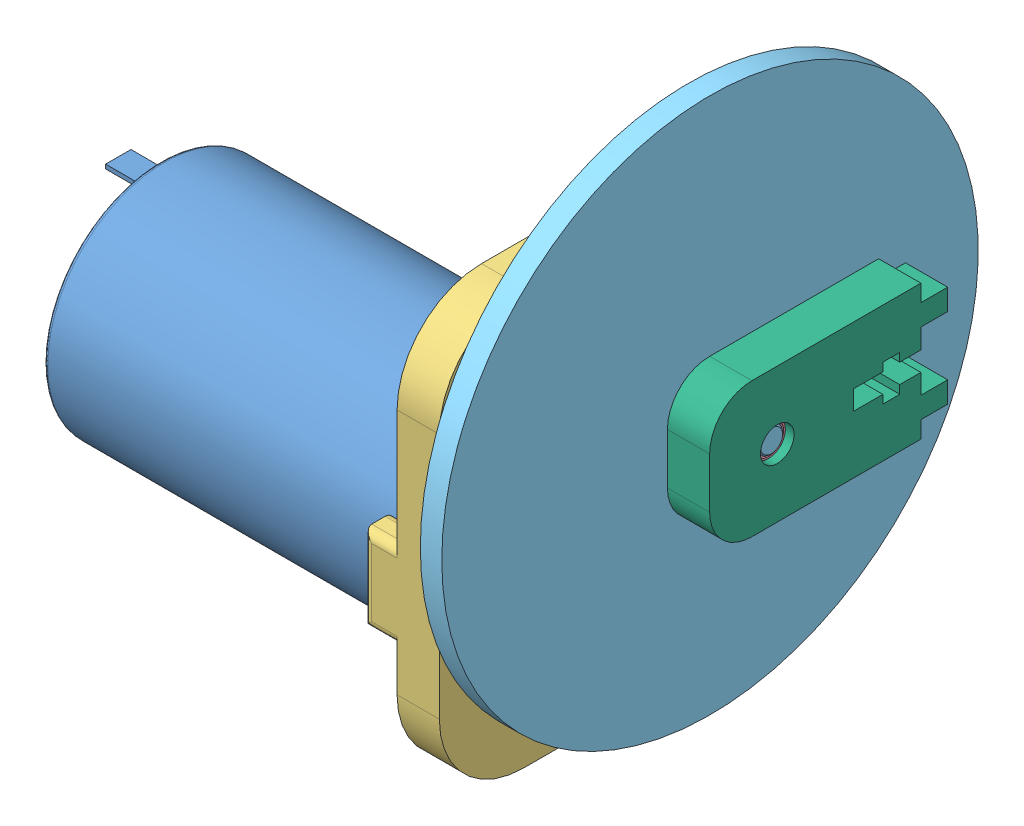
SolidWorks assembly dejonBot_gearBox, configuration Default. Lengths in mm.
Overall size (78 82.69 82.69).
7 component instances, 6 part files, 14 mates.
Components (placement in the parent):
- 6v DC motor AMAZON-1: 6v DC motor AMAZON [Default] at (-2.6863 41.6174 61.127) size (66.7 27.7 27.7)
- 12mmPD_13mmOD_2.5mmShaft_gearMOD-2: 12mmPD_13mmOD_2.5mmShaft_gearMOD [2662N28] at (55.0137 41.6174 61.127) x (0 -0.785836 -0.618435) z (-1 0 0) size (12.96 12.96 7.01)
- gearbox_plate-1: gearbox_plate [Default] at (42.3137 41.6174 61.127) x (1 0 0) z (0 1 0) size (9 37.17 49.2)
- 1_8inShaft bearing-1: 1_8inShaft bearing [Default] at (43.3513 62.8174 61.127) x (1 0 0) z (0 -0.004682 0.999989) size (3.97 9.53 9.53)
- wheel_gear_hybrid-1: wheel_gear_hybrid [2662N32] at (59.8137 62.8174 61.127) x (0 -0.926866 0.375392) z (-1 0 0) size (63.5 63.5 26.64)
- gearbox_plate_aux-1: gearbox_plate_aux [Default] at (65.3137 62.8174 56.627) x (0 -1 0) z (1 0 0) size (16 28.18 5)
- 1_8inShaft bearing-2: 1_8inShaft bearing [Default] at (65.3137 62.8174 61.127) x (1 0 0) z (0 -0.949547 0.313624) size (3.97 9.53 9.53)
Mates (geometry in assembly coordinates):
- Concentric1: concentric anti-aligned: cylinder of 6v DC motor AMAZON-1 through (59.0137 41.6174 61.127) axis (-1 0 0) radius 1.15; cylinder of 12mmPD_13mmOD_2.5mmShaft_gearMOD-2 through (42.3568 41.6174 61.127) axis (1 0 0) radius 1.25
- Distance1: distance = 1 mm anti-aligned: plane of 6v DC motor AMAZON-1 through (47.0137 41.6174 61.127) normal (1 0 0); plane of 12mmPD_13mmOD_2.5mmShaft_gearMOD-2 through (48.0137 40.3806 62.6987) normal (-1 0 0)
- Coincident7: coincident anti-aligned: plane of 6v DC motor AMAZON-1 through (44.3137 41.6174 61.127) normal (1 0 0); plane of gearbox_plate-1 through (44.3137 41.6174 61.127) normal (-1 0 0)
- Concentric5: concentric anti-aligned: cylinder of 6v DC motor AMAZON-1 through (39.3137 49.6174 61.127) axis (1 0 0) radius 1.5; circle of gearbox_plate-1
- Concentric6: concentric anti-aligned: cylinder of 6v DC motor AMAZON-1 through (39.3137 33.6174 61.127) axis (1 0 0) radius 1.5; cylinder of gearbox_plate-1 through (47.3147 33.6174 61.127) axis (-1 0 0) radius 1.6
- Concentric7: concentric anti-aligned: cylinder of gearbox_plate-1 through (43.3513 62.8174 61.127) axis (1 0 0) radius 4.9; cylinder of 1_8inShaft bearing-1 through (47.32 62.8174 61.127) axis (-1 0 0) radius 4.7625
- Coincident8: coincident anti-aligned: plane of gearbox_plate-1 through (43.3513 62.8174 61.127) normal (1 0 0); plane of 1_8inShaft bearing-1 through (43.3513 62.8174 61.127) normal (-1 0 0)
- Concentric11: concentric anti-aligned: cylinder of 1_8inShaft bearing-1 through (47.32 62.8174 61.127) axis (-1 0 0) radius 1.5875; cylinder of wheel_gear_hybrid-1 through (42.9957 62.8174 61.127) axis (1 0 0) radius 1.524
- Coincident11: coincident anti-aligned: plane of gearbox_plate-1 through (47.3137 41.6174 61.127) normal (1 0 0); plane of wheel_gear_hybrid-1 through (47.3137 62.8174 61.127) normal (-1 0 0)
- Distance3: distance = 18 mm anti-aligned: plane of gearbox_plate-1 through (47.3137 41.6174 61.127) normal (1 0 0); plane of gearbox_plate_aux-1 through (65.3137 62.8174 56.627) normal (-1 0 0)
- Concentric12: concentric aligned: cylinder of gearbox_plate_aux-1 through (69.2824 62.8174 61.127) axis (-1 0 0) radius 4.9; cylinder of 1_8inShaft bearing-2 through (69.2824 62.8174 61.127) axis (-1 0 0) radius 4.7625
- Coincident14: coincident anti-aligned: plane of gearbox_plate_aux-1 through (69.2824 62.8174 61.127) normal (-1 0 0); plane of 1_8inShaft bearing-2 through (69.2824 62.8174 61.127) normal (1 0 0)
- Concentric13: concentric aligned: cylinder of wheel_gear_hybrid-1 through (69.6317 62.8174 61.127) axis (-1 0 0) radius 1.524; cylinder of 1_8inShaft bearing-2 through (69.2824 62.8174 61.127) axis (-1 0 0) radius 1.5875
- Coincident17: coincident aligned: plane of gearbox_plate-1 through (47.3137 56.8174 44.127) normal (0 0 -1); plane of gearbox_plate_aux-1 through (70.3137 61.6674 44.127) normal (0 0 -1)
